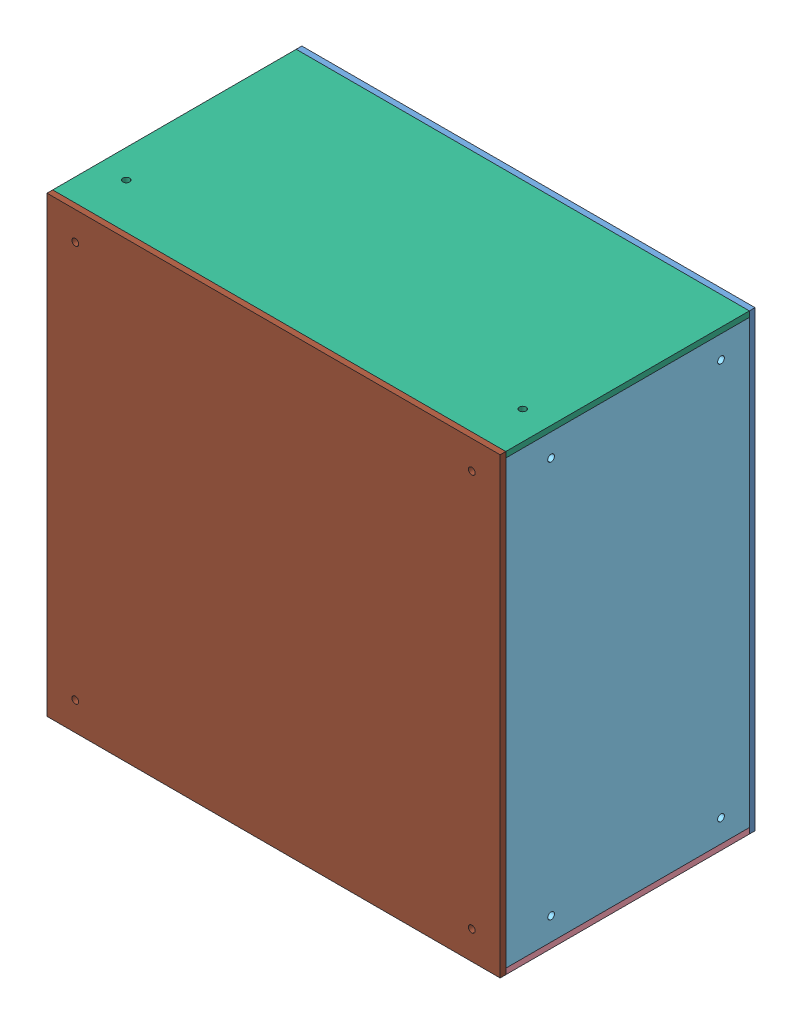
SolidWorks assembly Gehäuse, configuration Standard. Lengths in mm.
Overall size (160 160 90).
24 component instances, 11 part files, 46 mates.
Components (placement in the parent):
- bodenplate-2: bodenplate [Standard] at (-75.6824 5.2601 43.9445) size (160 160 2)
- winkel-seitenbefestigung-2: winkel-seitenbefestigung [Standard] at (-145.6824 75.2601 45.9445) x (-1 0 0) z (0 0 1) size (18 16 20)
- winkel-seitenbefestigung-3: winkel-seitenbefestigung [Standard] at (-5.6824 75.2601 45.9445) size (18 16 20)
- winkel-seitenbefestigung-4: winkel-seitenbefestigung [Standard] at (-145.6824 -64.7399 45.9445) x (-1 0 0) z (0 0 1) size (18 16 20)
- winkel-seitenbefestigung-6: winkel-seitenbefestigung [Standard] at (-5.6824 -64.7399 45.9445) size (18 16 20)
- abstandsbolzen-1: abstandsbolzen [Standard] at (-125.9939 -23.8324 45.9445) x (0.999896 -0.014432 0) z (0 0 1) size (5 5 10)
- abstandsbolzen-2: abstandsbolzen [Standard] at (-14.9939 -53.8324 45.9445) x (0.999896 -0.014432 0) z (0 0 1) size (5 5 10)
- abstandsbolzen-3: abstandsbolzen [Standard] at (-14.9939 60.1676 45.9445) x (0.999896 -0.014432 0) z (0 0 1) size (5 5 10)
- abstandsbolzen-4: abstandsbolzen [Standard] at (-128.9939 60.1676 45.9445) x (0.999896 -0.014432 0) z (0 0 1) size (5 5 10)
- seite_anschlüsse-1: seite_anschlüsse [Standard] at (-89.5922 -72.7399 59.0187) x (1 0 0) z (0 -1 0) size (160 86 2)
- seite_2malkurz-1: seite_2malkurz [Standard] at (4.3176 9.8812 62.7217) x (0 -1 0) z (-1 0 0) size (156 86 2)
- seite_2malkurz-2: seite_2malkurz [Standard] at (-153.6824 9.8812 62.7217) x (0 -1 0) z (-1 0 0) size (156 86 2)
- seite_back-1: seite_back [Standard] at (-94.844 85.2601 64.0774) x (1 0 0) z (0 -1 0) size (160 86 2)
- winkel-zwischen-1: winkel-zwischen [Standard] at (16.6639 -75.8975 105.9445) size (16 16 16)
- winkel-zwischen-2: winkel-zwischen [Standard] at (-156.8401 -87.0862 105.9445) x (0 -1 0) z (0 0 1) size (16 16 16)
- winkel-zwischen-3: winkel-zwischen [Standard] at (-168.0287 86.4178 105.9445) x (-1 0 0) z (0 0 1) size (16 16 16)
- winkel-zwischen-4: winkel-zwischen [Standard] at (5.4753 97.6064 105.9445) x (0 1 0) z (0 0 1) size (16 16 16)
- zwischenplatte-1: zwischenplatte [Standard] at (-81.2741 36.7602 107.4445) size (152 152 2)
- halter festplatte-1: halter festplatte [Standard] at (-153.6824 -4.0512 105.4109) x (0 0 -1) z (1 0 0) size (10 5 156)
- abstandsbolzen-deckel-1: abstandsbolzen-deckel [Standard] at (-140.7646 71.7817 109.4445) size (5 5 22.5)
- abstandsbolzen-deckel-2: abstandsbolzen-deckel [Standard] at (-0.7646 71.7817 109.4445) size (5 5 22.5)
- abstandsbolzen-deckel-3: abstandsbolzen-deckel [Standard] at (-140.7646 -68.2183 109.4445) size (5 5 22.5)
- abstandsbolzen-deckel-4: abstandsbolzen-deckel [Standard] at (-0.7646 -68.2183 109.4445) size (5 5 22.5)
- deckel-1: deckel [Standard] at (-99.9075 -27.6011 131.9445) size (160 160 2)
Mates (geometry in assembly coordinates):
- Deckungsgleich12: coincident: plane of winkel-seitenbefestigung-4 through (-135.6824 -72.7399 47.4445) normal (0 -1 0); plane of seite_anschlüsse-1 through (-155.6824 -72.7399 45.9445) normal (0 1 0)
- Konzentrisch1: concentric: circle of winkel-seitenbefestigung-4 centre (-153.6824 -64.7399 55.9445) axis (-1 0 0); circle of seite_2malkurz-2 centre (-153.6824 -64.7399 55.9445) axis (-1 0 0)
- Deckungsgleich13: coincident: plane of winkel-seitenbefestigung-4 through (-153.6824 -56.7399 47.9445) normal (-1 0 0); plane of seite_2malkurz-2 through (-153.6824 83.2601 45.9445) normal (1 0 0)
- Konzentrisch4: concentric: circle of winkel-seitenbefestigung-6 centre (2.3176 -64.7399 55.9445) axis (1 0 0); circle of seite_2malkurz-1 centre (2.3176 -64.7399 55.9445) axis (-1 0 0)
- Konzentrisch5: concentric: circle of winkel-seitenbefestigung-3 centre (2.3176 75.2601 55.9445) axis (1 0 0); circle of seite_2malkurz-1 centre (2.3176 75.2601 55.9445) axis (-1 0 0)
- Deckungsgleich14: coincident: plane of winkel-seitenbefestigung-3 through (2.3176 67.2601 47.9445) normal (1 0 0); plane of seite_2malkurz-1 through (2.3176 83.2601 45.9445) normal (-1 0 0)
- Konzentrisch2: concentric: circle of winkel-seitenbefestigung-2 centre (-153.6824 75.2601 55.9445) axis (-1 0 0); circle of seite_2malkurz-2 centre (-153.6824 75.2601 55.9445) axis (-1 0 0)
- Deckungsgleich17: coincident: plane of winkel-seitenbefestigung-2 through (-135.6824 83.2601 47.4445) normal (0 1 0); plane of seite_back-1 through (-155.6824 83.2601 45.9445) normal (0 -1 0)
- Konzentrisch6: concentric: circle of seite_2malkurz-1 centre (2.3176 -64.7399 115.9445) axis (-1 0 0); circle of winkel-zwischen-1 centre (2.3176 -64.7399 115.9445) axis (1 0 0)
- Konzentrisch7: concentric: circle of seite_anschlüsse-1 centre (-5.6824 -72.7399 115.9445) axis (0 -1 0); circle of winkel-zwischen-1 centre (-5.6824 -72.7399 115.9445) axis (0 -1 0)
- Konzentrisch8: concentric: circle of seite_2malkurz-1 centre (2.3176 75.2601 115.9445) axis (-1 0 0); circle of winkel-zwischen-4 centre (2.3176 75.2601 115.9445) axis (1 0 0)
- Konzentrisch10: concentric: circle of seite_back-1 centre (-5.6824 83.2601 115.9445) axis (0 -1 0); circle of winkel-zwischen-4 centre (-5.6824 83.2601 115.9445) axis (0 1 0)
- Konzentrisch11: concentric: circle of seite_2malkurz-2 centre (-153.6824 -64.7399 115.9445) axis (-1 0 0); circle of winkel-zwischen-2 centre (-153.6824 -64.7399 115.9445) axis (-1 0 0)
- Konzentrisch12: concentric: circle of seite_anschlüsse-1 centre (-145.6824 -72.7399 115.9445) axis (0 -1 0); circle of winkel-zwischen-2 centre (-145.6824 -72.7399 115.9445) axis (0 -1 0)
- Konzentrisch13: concentric: circle of seite_back-1 centre (-145.6824 83.2601 115.9445) axis (0 -1 0); circle of winkel-zwischen-3 centre (-145.6824 83.2601 115.9445) axis (0 1 0)
- Konzentrisch14: concentric: circle of seite_2malkurz-2 centre (-153.6824 75.2601 115.9445) axis (-1 0 0); circle of winkel-zwischen-3 centre (-153.6824 75.2601 115.9445) axis (-1 0 0)
- Konzentrisch15: concentric: circle of winkel-zwischen-1 centre (-5.6824 -64.7399 107.4445) axis (0 0 1); circle of zwischenplatte-1 centre (-5.6824 -64.7399 107.4445) axis (0 0 1)
- Deckungsgleich18: coincident: plane of winkel-zwischen-3 through (-137.6824 81.2601 107.4445) normal (0 0 1); circle of zwischenplatte-1 centre (-145.6824 75.2601 107.4445) axis (0 0 1)
- Deckungsgleich20: coincident: plane of seite_anschlüsse-1 through (-155.6824 -72.7399 45.9445) normal (0 1 0); plane of seite_2malkurz-2 through (-155.6824 -72.7399 131.9445) normal (0 -1 0)
- Deckungsgleich21: coincident: plane of seite_back-1 through (-155.6824 83.2601 45.9445) normal (0 -1 0); plane of seite_2malkurz-2 through (-155.6824 83.2601 131.9445) normal (0 1 0)
- Deckungsgleich22: coincident: plane of seite_2malkurz-1 through (2.3176 83.2601 131.9445) normal (0 1 0); plane of seite_back-1 through (-155.6824 83.2601 45.9445) normal (0 -1 0)
- Deckungsgleich23: coincident: plane of seite_anschlüsse-1 through (-155.6824 -72.7399 45.9445) normal (0 1 0); plane of seite_2malkurz-1 through (2.3176 -72.7399 131.9445) normal (0 -1 0)
- Konzentrisch20: concentric: circle of winkel-zwischen-4 centre (-5.6824 75.2601 107.4445) axis (0 0 1); circle of zwischenplatte-1 centre (-5.6824 75.2601 107.4445) axis (0 0 1)
- Deckungsgleich24: coincident: plane of seite_2malkurz-1 through (2.3176 83.2601 45.9445) normal (0 0 -1); plane of seite_back-1 through (-155.6824 83.2601 45.9445) normal (0 0 -1)
- Deckungsgleich25: coincident: plane of seite_anschlüsse-1 through (-155.6824 -74.7399 45.9445) normal (0 0 -1); plane of seite_2malkurz-2 through (-155.6824 83.2601 45.9445) normal (0 0 -1)
- Deckungsgleich26: coincident: plane of seite_2malkurz-2 through (-155.6824 83.2601 45.9445) normal (0 0 -1); plane of seite_back-1 through (-155.6824 83.2601 45.9445) normal (0 0 -1)
- Deckungsgleich28: coincident: plane of seite_2malkurz-1 through (2.3176 83.2601 45.9445) normal (-1 0 0); plane of winkel-zwischen-1 through (2.3176 -70.7399 121.9445) normal (1 0 0)
- Deckungsgleich29: coincident: plane of seite_2malkurz-2 through (-153.6824 83.2601 45.9445) normal (1 0 0); plane of winkel-zwischen-2 through (-153.6824 -70.7399 121.9445) normal (-1 0 0)
- Deckungsgleich30: coincident: plane of winkel-seitenbefestigung-6 through (2.3176 -72.7399 47.9445) normal (1 0 0); plane of seite_2malkurz-1 through (2.3176 83.2601 45.9445) normal (-1 0 0)
- Deckungsgleich31: coincident: plane of winkel-seitenbefestigung-6 through (-15.6824 -72.7399 47.4445) normal (0 -1 0); plane of seite_anschlüsse-1 through (-155.6824 -72.7399 45.9445) normal (0 1 0)
- Deckungsgleich35: coincident: plane of winkel-seitenbefestigung-2 through (-153.6824 83.2601 47.9445) normal (-1 0 0); plane of seite_2malkurz-2 through (-153.6824 83.2601 45.9445) normal (1 0 0)
- Deckungsgleich36: coincident: circle of bodenplate-2 centre (-145.6824 75.2601 45.9445) axis (0 0 1); circle of winkel-seitenbefestigung-2 centre (-145.6824 75.2601 45.9445) axis (0 0 1)
- Deckungsgleich37: coincident: circle of bodenplate-2 centre (-5.6824 -64.7399 45.9445) axis (0 0 1); circle of winkel-seitenbefestigung-6 centre (-5.6824 -64.7399 45.9445) axis (0 0 1)
- Deckungsgleich38: coincident aligned: circle of bodenplate-2 centre (-132.6824 62.2601 45.9445) axis (0 0 1); circle of abstandsbolzen-4 centre (-132.6824 62.2601 45.9445) axis (0 0 1)
- Deckungsgleich39: coincident aligned: circle of bodenplate-2 centre (-18.6824 62.2601 45.9445) axis (0 0 1); circle of abstandsbolzen-3 centre (-18.6824 62.2601 45.9445) axis (0 0 1)
- Deckungsgleich40: coincident aligned: circle of bodenplate-2 centre (-18.6824 -51.7399 45.9445) axis (0 0 1); circle of abstandsbolzen-2 centre (-18.6824 -51.7399 45.9445) axis (0 0 1)
- Deckungsgleich41: coincident aligned: circle of bodenplate-2 centre (-129.6824 -21.7399 45.9445) axis (0 0 1); circle of abstandsbolzen-1 centre (-129.6824 -21.7399 45.9445) axis (0 0 1)
- Deckungsgleich42: coincident: plane of seite_2malkurz-1 through (2.3176 83.2601 45.9445) normal (-1 0 0); plane of halter festplatte-1 through (2.3176 10.2601 119.4445) normal (1 0 0)
- Abstand1: distance = 70 mm: plane of seite_back-1 through (-155.6824 85.2601 45.9445) normal (0 1 0); line of halter festplatte-1
- Deckungsgleich44: coincident: plane of zwischenplatte-1 through (-151.6824 -70.7399 109.4445) normal (0 0 1); plane of halter festplatte-1 through (2.3176 15.2601 109.4445) normal (0 0 -1)
- Deckungsgleich45: coincident: circle of zwischenplatte-1 centre (-5.6824 -64.7399 109.4445) axis (0 0 1); circle of abstandsbolzen-deckel-4 centre (-5.6824 -64.7399 109.4445) axis (0 0 1)
- Deckungsgleich46: coincident aligned: circle of zwischenplatte-1 centre (-145.6824 -64.7399 109.4445) axis (0 0 1); circle of abstandsbolzen-deckel-3 centre (-145.6824 -64.7399 109.4445) axis (0 0 1)
- Deckungsgleich47: coincident aligned: circle of zwischenplatte-1 centre (-145.6824 75.2601 109.4445) axis (0 0 1); circle of abstandsbolzen-deckel-1 centre (-145.6824 75.2601 109.4445) axis (0 0 1)
- Deckungsgleich48: coincident: circle of zwischenplatte-1 centre (-5.6824 75.2601 109.4445) axis (0 0 1); circle of abstandsbolzen-deckel-2 centre (-5.6824 75.2601 109.4445) axis (0 0 1)
- Deckungsgleich49: coincident: circle of abstandsbolzen-deckel-4 centre (-5.6824 -64.7399 131.9445) axis (0 0 1); circle of deckel-1 centre (-5.6824 -64.7399 131.9445) axis (0 0 1)
- Konzentrisch21: concentric aligned: circle of abstandsbolzen-deckel-1; circle of deckel-1
